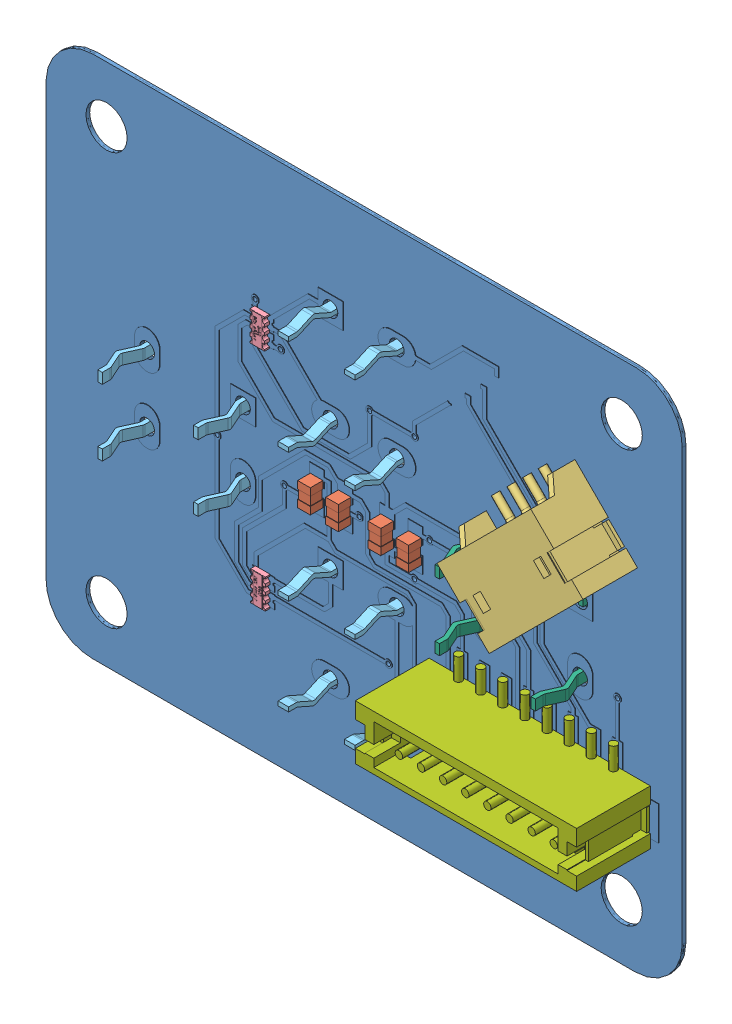
SolidWorks assembly pcb_buttons, configuration Default. Lengths in mm.
Overall size (43.5 35.88 10.33).
28 component instances, 9 part files, 0 mates.
Components (placement in the parent):
- Dip_buttons-1: Dip_buttons [Default] at origin size (43.5 35.88 0.32)
- Capacitor 0603_buttons-1: Capacitor 0603_buttons [Default] at (-1.2809 -0.2801 0.352) x (0 -1 0) z (-1 0 0) size (1.6 0.86 0.86)
- Capacitor 0603_buttons-2: Capacitor 0603_buttons [Default] at (-3.1859 -0.2507 0.352) x (0 -1 0) z (-1 0 0) size (1.6 0.86 0.86)
- Capacitor 0603_buttons-3: Capacitor 0603_buttons [Default] at (1.5918 -0.2507 0.352) x (0 -1 0) z (-1 0 0) size (1.6 0.86 0.86)
- Capacitor 0603_buttons-4: Capacitor 0603_buttons [Default] at (3.4811 -0.2948 0.352) x (0 -1 0) z (-1 0 0) size (1.6 0.86 0.86)
- Hole_Hole_buttons-1: Hole_Hole_buttons [Default] at (-17.462 13.97 0.322)
- Hole_Hole_buttons-2: Hole_Hole_buttons [Default] at (17.462 -13.97 0.322)
- Hole_Hole_buttons-3: Hole_Hole_buttons [Default] at (17.462 13.97 0.322)
- Hole_Hole_buttons-4: Hole_Hole_buttons [Default] at (-17.462 -13.97 0.322)
- S4B-ZR-SM4A-TF_buttons-1: S4B-ZR-SM4A-TF_buttons [Default] at (11.146 7.143 0.322) x (0.707107 0.707107 0) z (0.707107 -0.707107 0) size (9 3.7 6.5)
- 4xRes_0402_buttons-1: 4xRes_0402_buttons [По умолчанию] at (-6.8859 7.489 0.322) x (0 -1 0) z (-1 0 0) size (2 0.37 1)
- 4xRes_0402_buttons-2: 4xRes_0402_buttons [По умолчанию] at (-6.8317 -7.7471 0.322) x (0 -1 0) z (-1 0 0) size (2 0.37 1)
- Tactile switch 6x6x5mm_buttons-1: Tactile switch 6x6x5mm_buttons [Valor predeterminado] at (0 7.62 0) x (1 0 0) z (0 1 0) size (6.03 8.52 7.74)
- Tactile switch 6x6x5mm_buttons-2: Tactile switch 6x6x5mm_buttons [Valor predeterminado] at (-11.43 0 0) x (0 -1 0) z (1 0 0) size (6.03 8.52 7.74)
- Tactile switch 6x6x5mm_buttons-3: Tactile switch 6x6x5mm_buttons [Valor predeterminado] at (0 -7.62 0) x (1 0 0) z (0 1 0) size (6.03 8.52 7.74)
- Tactile switch 6x6x5mm_buttons_CUT-1: Tactile switch 6x6x5mm_buttons_CUT [Valor predeterminado] at (11.43 0 0) x (0 -1 0) z (1 0 0) size (6.03 8.52 7.74)
- B8B-PH-SM4_buttons-1: B8B-PH-SM4_buttons [Default] at (11.938 -9.982 0.322) x (1 0 0) z (0 -1 0) size (15 5 5.2)
- Via_Via_buttons-1: Via_Via_buttons [Default] at (4.45 0.635 0.322)
- Via_Via_buttons-2: Via_Via_buttons [Default] at (-7.366 8.89 0.322)
- Via_Via_buttons-3: Via_Via_buttons [Default] at (3.43 -2.148 0.322)
- Via_Via_buttons-4: Via_Via_buttons [Default] at (3.43 6.223 0.322)
- Via_Via_buttons-5: Via_Via_buttons [Default] at (-9.944 -0.354 0.322)
- Via_Via_buttons-6: Via_Via_buttons [Default] at (-0.313 -0.354 0.322)
- Via_Via_buttons-7: Via_Via_buttons [Default] at (0.398 6.223 0.322)
- Via_Via_buttons-8: Via_Via_buttons [Default] at (-5.377 -1.065 0.322)
- Via_Via_buttons-9: Via_Via_buttons [Default] at (17.196 -2.25 0.322)
- Via_Via_buttons-10: Via_Via_buttons [Default] at (1.666 -8.001 0.322)
- Via_Via_buttons-11: Via_Via_buttons [Default] at (-5.645 6.807 0.322)
